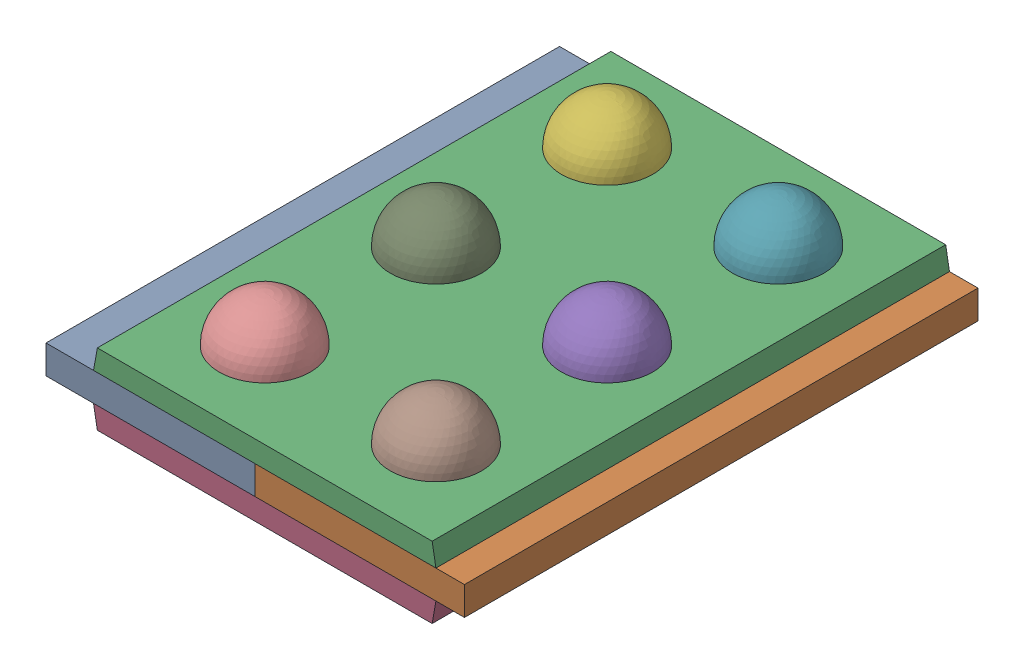
SolidWorks assembly rivet_assem, configuration Default. Lengths in mm.
Overall size (132 51.3 162).
10 component instances, 3 part files, 18 mates.
Components (placement in the parent):
- Butt plate-3: Butt plate [Default] at (-90.2807 21.592 30.6615) size (66 9 162)
- Butt plate-4: Butt plate [Default] at (-21.3164 21.592 -2.4518) x (-1 0 0) z (0 0 -1) size (66 9 162)
- Cover plate-1: Cover plate [Default] at (-61.378 30.592 31.5161) size (108 6.75 162)
- Cover plate-2: Cover plate [Default] at (-44.2191 21.592 31.5161) x (-1 0 0) z (0 0 1) size (108 6.75 162)
- Rivet-1: Rivet [Default] at (-23.5725 18.6074 14.1049) size (28.8 51.3 28.8)
- Rivet-2: Rivet [Default] at (-77.5725 18.6074 -39.8951) size (28.8 51.3 28.8)
- Rivet-3: Rivet [Default] at (-23.5725 18.6074 -39.8951) size (28.8 51.3 28.8)
- Rivet-4: Rivet [Default] at (-23.5725 18.6074 68.1049) size (28.8 51.3 28.8)
- Rivet-5: Rivet [Default] at (-77.5725 18.6074 14.1049) size (28.8 51.3 28.8)
- Rivet-6: Rivet [Default] at (-77.5725 18.6074 68.1049) size (28.8 51.3 28.8)
Mates (geometry in assembly coordinates):
- Coincident6: coincident anti-aligned: plane of Butt plate-3 through (-55.7986 30.592 -66.8951) normal (1 0 0); plane of Butt plate-4 through (-55.7986 30.592 95.1048) normal (-1 0 0)
- Lock2: lock: unknown of Butt plate-3; unknown of Butt plate-4
- Concentric2: concentric aligned: cylinder of Butt plate-3 through (-79.7986 30.592 68.1049) axis (0 -1 0) radius 9; cylinder of Cover plate-1 through (-79.7986 37.342 68.1049) axis (0 -1 0) radius 9
- Coincident8: coincident anti-aligned: plane of Butt plate-3 through (-90.2807 30.592 30.6615) normal (0 1 0); plane of Cover plate-1 through (-61.378 30.592 31.5161) normal (0 -1 0)
- Concentric3: concentric anti-aligned: cylinder of Butt plate-3 through (-79.7986 30.592 -39.8951) axis (0 -1 0) radius 9; cylinder of Cover plate-2 through (-79.7986 14.842 -39.8951) axis (0 1 0) radius 9
- Coincident9: coincident anti-aligned: plane of Butt plate-3 through (-90.2807 21.592 30.6615) normal (0 -1 0); plane of Cover plate-2 through (-44.2191 21.592 31.5161) normal (0 1 0)
- Concentric4: concentric anti-aligned: cylinder of Cover plate-1 through (-25.7986 37.342 -39.8951) axis (0 -1 0) radius 9; cylinder of Rivet-3 through (-25.7986 51.742 -39.8951) axis (0 1 0) radius 9
- Coincident10: coincident anti-aligned: plane of Cover plate-1 through (-61.378 37.342 31.5161) normal (0 1 0); plane of Rivet-3 through (-16.7986 37.342 -39.8951) normal (0 -1 0)
- Concentric5: concentric anti-aligned: cylinder of Cover plate-1 through (-25.7986 37.342 14.1049) axis (0 -1 0) radius 9; cylinder of Rivet-1 through (-25.7986 51.742 14.1049) axis (0 1 0) radius 9
- Concentric6: concentric anti-aligned: cylinder of Cover plate-1 through (-25.7986 37.342 68.1049) axis (0 -1 0) radius 9; cylinder of Rivet-4 through (-25.7986 51.742 68.1049) axis (0 1 0) radius 9
- Concentric7: concentric anti-aligned: cylinder of Cover plate-1 through (-79.7986 37.342 -39.8951) axis (0 -1 0) radius 9; cylinder of Rivet-2 through (-79.7986 51.742 -39.8951) axis (0 1 0) radius 9
- Concentric8: concentric anti-aligned: cylinder of Cover plate-1 through (-79.7986 37.342 14.1049) axis (0 -1 0) radius 9; cylinder of Rivet-5 through (-79.7986 51.742 14.1049) axis (0 1 0) radius 9
- Concentric9: concentric anti-aligned: cylinder of Cover plate-1 through (-79.7986 37.342 68.1049) axis (0 -1 0) radius 9; cylinder of Rivet-6 through (-79.7986 57.9115 68.1049) axis (0 1 0) radius 9
- Coincident11: coincident anti-aligned: plane of Cover plate-1 through (-61.378 37.342 31.5161) normal (0 1 0); plane of Rivet-1 through (-16.7986 37.342 14.1049) normal (0 -1 0)
- Coincident13: coincident anti-aligned: plane of Cover plate-1 through (-61.378 37.342 31.5161) normal (0 1 0); plane of Rivet-4 through (-16.7986 37.342 68.1049) normal (0 -1 0)
- Coincident14: coincident anti-aligned: plane of Cover plate-1 through (-61.378 37.342 31.5161) normal (0 1 0); plane of Rivet-2 through (-70.7986 37.342 -39.8951) normal (0 -1 0)
- Coincident15: coincident anti-aligned: plane of Cover plate-1 through (-61.378 37.342 31.5161) normal (0 1 0); plane of Rivet-5 through (-70.7986 37.342 14.1049) normal (0 -1 0)
- Coincident16: coincident anti-aligned: plane of Cover plate-1 through (-61.378 37.342 31.5161) normal (0 1 0); plane of Rivet-6 through (-70.7986 37.342 68.1049) normal (0 -1 0)
